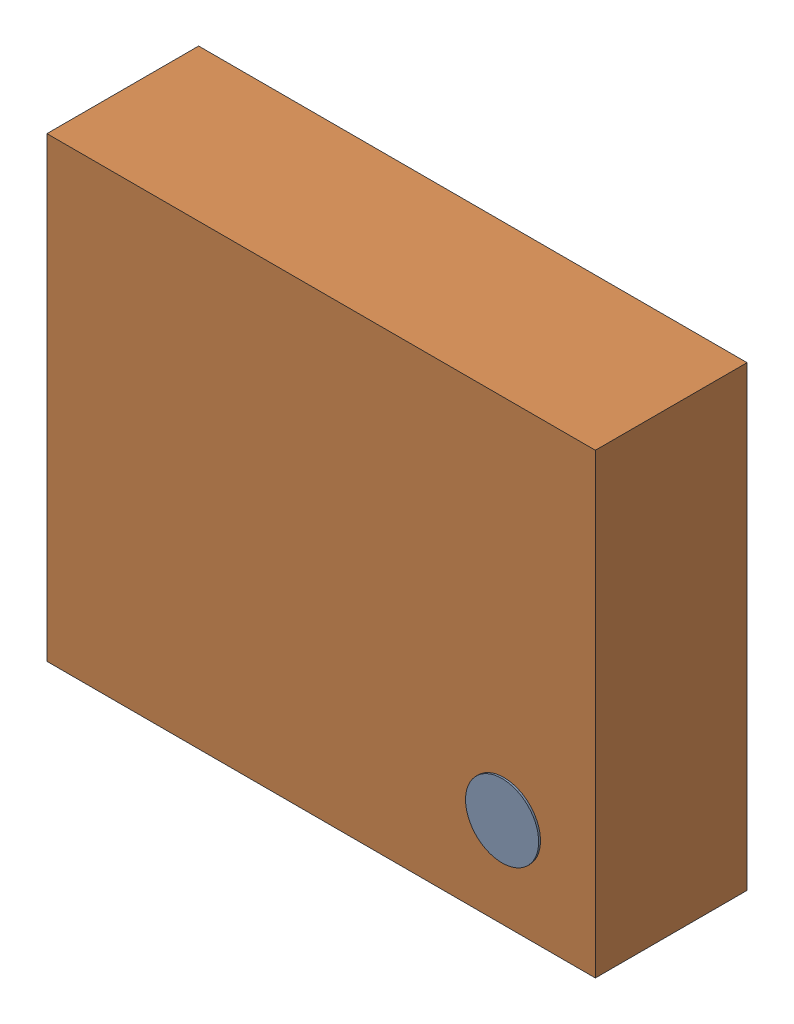
SolidWorks assembly U15, configuration Standard. Lengths in mm.
Overall size (3 2.5 0.84).
4 component instances, 2 part files, 0 mates.
Components (placement in the parent):
- 6074061904-1: 6074061904 [Standard] at (5.2999 8.0499 0.8) x (-1 0 0) z (0 0 1) size (0.4 0.4 0.04)
  - Cylinder-1: Cylinder [Standard] at origin size (0.4 0.4 0.04)
- 6094290864-1: 6094290864 [Standard] at (4.3 8.8 0) size (3 2.5 0.83)
  - Extruded-2-1: Extruded-2 [Standard] at origin size (3 2.5 0.83)
